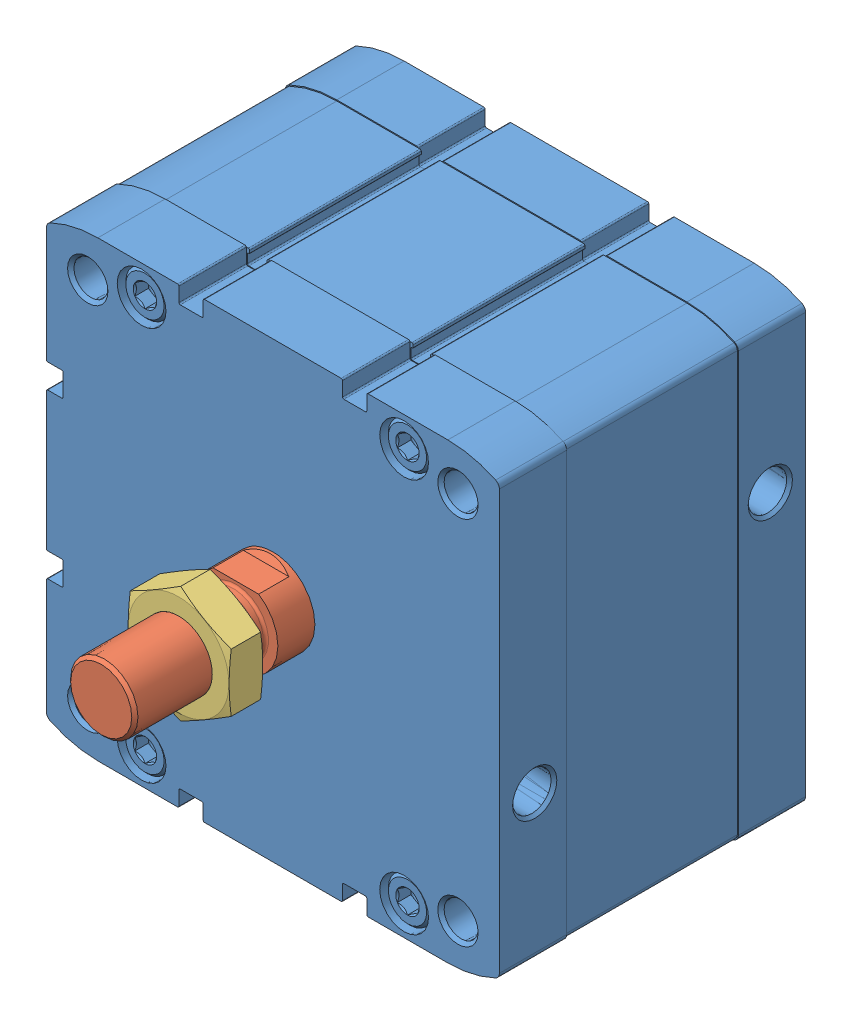
SolidWorks assembly 536393 ADN-125-10-A-P-A---(0), configuration Default. Lengths in mm.
Overall size (134.6 134.6 142).
3 component instances, 3 part files, 6 mates.
Components (placement in the parent):
- 536393 ADN-10-P---(Z)-1: 536393 ADN-10-P---(Z) [Default] at origin size (134.6 134.6 91)
- 536393 ADN-10-P-A_(KS)-1: 536393 ADN-10-P-A_(KS) [Default] x (0 0 -1) z (-1 0 0) size (121 125 125)
- DIN-439-B - M20x1_5(F)-1: DIN-439-B - M20x1_5(F) [Default] at (0 0 28) x (1 0 0) z (0 -1 0) size (30 10 34.64)
Mates (geometry in assembly coordinates):
- LimitDistance1: limit distance = 0 mm anti-aligned: plane of 536393 ADN-10-P---(Z)-1 through (0 0 -70) normal (0 0 1); plane of 536393 ADN-10-P-A_(KS)-1 through (0 0 -70) normal (0 0 -1)
- Coincident1: coincident anti-aligned: line of 536393 ADN-10-P---(Z)-1 through (0 0 80.9) axis (0 0 -1); line of 536393 ADN-10-P-A_(KS)-1 through (0 0 -80.9) axis (0 0 1)
- Angle3: planar angle = 0 rad aligned: plane of 536393 ADN-10-P-A_(KS)-1 through (0 0 0) normal (1 0 0); plane of 536393 ADN-10-P---(Z)-1 through (0 0 0) normal (1 0 0)
- Distance1: distance = 0 mm anti-aligned: plane of 536393 ADN-10-P-A_(KS)-1 through (0 0 23) normal (0 0 -1); plane of DIN-439-B - M20x1_5(F)-1 through (0 0 23) normal (0 0 1)
- Coincident2: coincident anti-aligned: line of 536393 ADN-10-P-A_(KS)-1 through (0 0 -80.9) axis (0 0 1); line of DIN-439-B - M20x1_5(F)-1 through (0 0 78) axis (0 0 -1)
- Angle6: planar angle = 0 rad aligned: plane of DIN-439-B - M20x1_5(F)-1 through (0 0 28) normal (1 0 0); plane of 536393 ADN-10-P-A_(KS)-1 through (0 0 0) normal (1 0 0)
